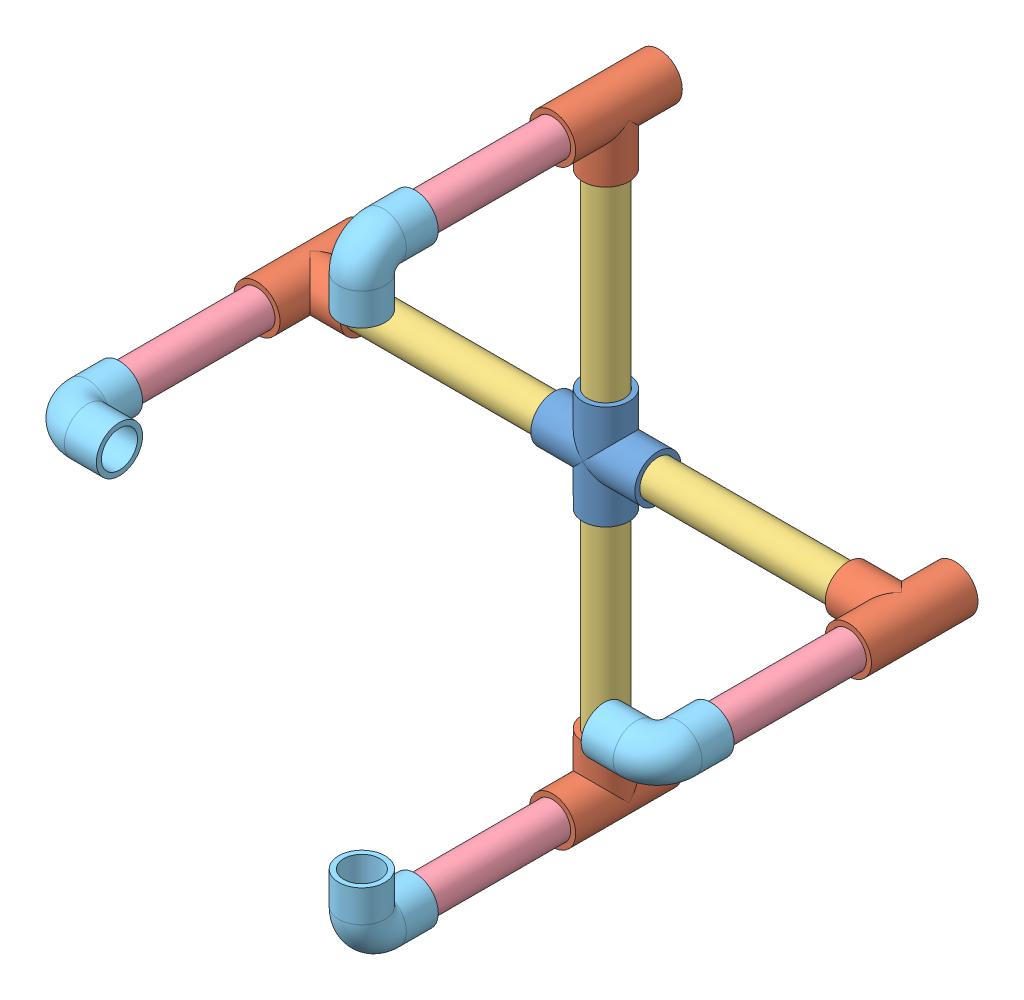
SolidWorks assembly WAYPOINT, configuration Default. Lengths in mm.
Overall size (379.95 379.95 190.93).
17 component instances, 5 part files, 37 mates.
Components (placement in the parent):
- 1-2 PVC CROSS-1: 1-2 PVC CROSS [4880K241] at (26.3836 29.7217 47.5538) size (61.91 61.91 27.56)
- 1-2 PVC TEE-1: 1-2 PVC TEE [4880K41] at (26.3836 -146.472 47.5538) x (0 0 1) z (-1 0 0) size (63.5 45.53 27.56)
- 1-2 PVC TEE-2: 1-2 PVC TEE [4880K41] at (202.5773 29.7217 47.5538) x (0 0 -1) z (0 1 0) size (63.5 45.53 27.56)
- 1-2 PVC TEE-3: 1-2 PVC TEE [4880K41] at (-149.8102 29.7217 47.5538) x (0 0 -1) z (0 -1 0) size (63.5 45.53 27.56)
- 1-2 PVC TEE-4: 1-2 PVC TEE [4880K41] at (26.3836 205.9155 47.5538) x (0 0 1) z (1 0 0) size (63.5 45.53 27.56)
- 1-2 PVC PIPE 15CM-1: 1-2 PVC PIPE 15CM [48925K91] at (26.3836 -58.772 47.5538) x (1 0 0) z (0 1 0) size (21.34 21.34 150)
- 1-2 PVC PIPE 15CM-2: 1-2 PVC PIPE 15CM [48925K91] at (-62.1102 29.7217 47.5538) x (0 0.375424 0.926853) z (-1 0 0) size (21.34 21.34 150)
- 1-2 PVC PIPE 15CM-3: 1-2 PVC PIPE 15CM [48925K91] at (26.3836 118.2155 47.5538) x (1 0 0) z (0 -1 0) size (21.34 21.34 150)
- 1-2 PVC PIPE 15CM-4: 1-2 PVC PIPE 15CM [48925K91] at (114.8773 29.7217 47.5538) x (0 0.732545 -0.680718) z (1 0 0) size (21.34 21.34 150)
- 1-2 PVC PIPE 12CM-1: 1-2 PVC PIPE 12CM [48925K91] at (-149.8102 29.7217 120.2538) x (1 0 0) z (0 0 -1) size (21.34 21.34 120)
- 1-2 PVC PIPE 12CM-2: 1-2 PVC PIPE 12CM [48925K91] at (26.3836 205.9155 120.2538) x (-1 0 0) z (0 0 -1) size (21.34 21.34 120)
- 1-2 PVC PIPE 12CM-3: 1-2 PVC PIPE 12CM [48925K91] at (202.5773 29.7217 120.2538) x (1 0 0) z (0 0 -1) size (21.34 21.34 120)
- 1-2 PVC PIPE 12CM-4: 1-2 PVC PIPE 12CM [48925K91] at (26.3836 -146.472 120.2538) x (0.346484 -0.938056 0) z (0 0 -1) size (21.34 21.34 120)
- 1-2 PVC ELBOW-1: 1-2 PVC ELBOW [4880K21] at (-149.8102 29.7217 192.9538) x (-1 0 0) z (0 -1 0) size (45.53 45.53 27.56)
- 1-2 PVC ELBOW-2: 1-2 PVC ELBOW [4880K21] at (26.3836 205.9155 192.9538) x (0 0 1) z (1 0 0) size (45.53 45.53 27.56)
- 1-2 PVC ELBOW-3: 1-2 PVC ELBOW [4880K21] at (202.5773 29.7217 192.9538) x (1 0 0) z (0 1 0) size (45.53 45.53 27.56)
- 1-2 PVC ELBOW-4: 1-2 PVC ELBOW [4880K21] at (26.3836 -146.472 192.9538) x (0 -1 0) z (1 0 0) size (45.53 45.53 27.56)
Mates (geometry in assembly coordinates):
- Concentric1: concentric aligned: cone of 1-2 PVC CROSS-1 through (57.3398 29.7217 47.5538) axis (-1 0 0); cylinder of 1-2 PVC PIPE 15CM-4 through (189.8773 29.7217 47.5538) axis (-1 0 0) radius 10.668
- Coincident1: coincident anti-aligned: plane of 1-2 PVC CROSS-1 through (39.8773 29.7217 47.5538) normal (1 0 0); plane of 1-2 PVC PIPE 15CM-4 through (39.8773 29.7217 47.5538) normal (-1 0 0)
- Concentric2: concentric anti-aligned: cylinder of 1-2 PVC CROSS-1 through (39.8773 29.7217 47.5538) axis (-1 0 0) radius 13.7795; cylinder of 1-2 PVC PIPE 15CM-2 through (-137.1102 29.7217 47.5538) axis (1 0 0) radius 10.668
- Coincident2: coincident anti-aligned: plane of 1-2 PVC CROSS-1 through (12.8898 29.7217 47.5538) normal (-1 0 0); plane of 1-2 PVC PIPE 15CM-2 through (12.8898 29.7217 47.5538) normal (1 0 0)
- Coincident3: coincident anti-aligned: plane of 1-2 PVC CROSS-1 through (26.3836 43.2155 47.5538) normal (0 1 0); plane of 1-2 PVC PIPE 15CM-3 through (26.3836 43.2155 47.5538) normal (0 -1 0)
- Concentric3: concentric anti-aligned: cone of 1-2 PVC CROSS-1 through (26.3836 60.678 47.5538) axis (0 -1 0); cylinder of 1-2 PVC PIPE 15CM-3 through (26.3836 43.2155 47.5538) axis (0 1 0) radius 10.668
- Coincident4: coincident anti-aligned: plane of 1-2 PVC CROSS-1 through (26.3836 16.228 47.5538) normal (0 -1 0); plane of 1-2 PVC PIPE 15CM-1 through (26.3836 16.228 47.5538) normal (0 1 0)
- Concentric4: concentric anti-aligned: cone of 1-2 PVC CROSS-1 through (26.3836 16.228 47.5538) axis (0 1 0); cylinder of 1-2 PVC PIPE 15CM-1 through (26.3836 16.228 47.5538) axis (0 -1 0) radius 10.668
- Coincident5: coincident anti-aligned: plane of 1-2 PVC TEE-2 through (189.8773 29.7217 47.5538) normal (-1 0 0); plane of 1-2 PVC PIPE 15CM-4 through (189.8773 29.7217 47.5538) normal (1 0 0)
- Concentric5: concentric anti-aligned: cylinder of 1-2 PVC TEE-2 through (202.5773 29.7217 47.5538) axis (1 0 0) radius 13.7795; cylinder of 1-2 PVC PIPE 15CM-4 through (189.8773 29.7217 47.5538) axis (-1 0 0) radius 10.668
- Concentric6: concentric aligned: cylinder of 1-2 PVC PIPE 12CM-3 through (202.5773 29.2349 60.2445) axis (0 -0.038332 0.999265) radius 10.668; cone of 1-2 PVC ELBOW-3 through (202.5773 25.3653 161.1203) axis (0 -0.038332 0.999265)
- Coincident6: coincident anti-aligned: plane of 1-2 PVC PIPE 12CM-3; plane of 1-2 PVC ELBOW-3
- Concentric7: concentric aligned: cone of 1-2 PVC TEE-2 through (202.5773 30.9387 15.8272) axis (0 -0.038332 0.999265); cylinder of 1-2 PVC PIPE 12CM-3 through (202.5773 29.2349 60.2445) axis (0 -0.038332 0.999265) radius 10.668
- Concentric8: concentric aligned: cone of 1-2 PVC TEE-1 through (26.3836 -114.722 47.5538) axis (0 -1 0); cylinder of 1-2 PVC PIPE 15CM-1 through (26.3836 16.228 47.5538) axis (0 -1 0) radius 10.668
- Coincident7: coincident anti-aligned: plane of 1-2 PVC TEE-1 through (26.3836 -133.772 47.5538) normal (0 1 0); plane of 1-2 PVC PIPE 15CM-1 through (26.3836 -133.772 47.5538) normal (0 -1 0)
- Coincident8: coincident anti-aligned: plane of 1-2 PVC TEE-4 through (26.3836 193.2155 47.5538) normal (0 -1 0); plane of 1-2 PVC PIPE 15CM-3 through (26.3836 193.2155 47.5538) normal (0 1 0)
- Concentric9: concentric aligned: cylinder of 1-2 PVC TEE-4 through (26.3836 205.9155 47.5538) axis (0 1 0) radius 13.7795; cylinder of 1-2 PVC PIPE 15CM-3 through (26.3836 43.2155 47.5538) axis (0 1 0) radius 10.668
- Coincident9: coincident anti-aligned: plane of 1-2 PVC TEE-4 through (26.3836 205.9155 60.2538) normal (0 0 1); plane of 1-2 PVC PIPE 12CM-2 through (26.3836 205.9155 60.2538) normal (0 0 -1)
- Concentric10: concentric anti-aligned: cone of 1-2 PVC TEE-4 through (26.3836 205.9155 79.3038) axis (0 0 -1); cylinder of 1-2 PVC PIPE 12CM-2 through (26.3836 205.9155 60.2538) axis (0 0 1) radius 10.668
- Coincident10: coincident anti-aligned: plane of 1-2 PVC PIPE 12CM-2 through (26.3836 205.9155 180.2538) normal (0 0 1); plane of 1-2 PVC ELBOW-2 through (26.3836 205.9155 180.2538) normal (0 0 -1)
- Concentric11: concentric aligned: cylinder of 1-2 PVC PIPE 12CM-2 through (26.3836 205.9155 60.2538) axis (0 0 1) radius 10.668; cone of 1-2 PVC ELBOW-2 through (26.3836 205.9155 180.2538) axis (0 0 1)
- Coincident11: coincident anti-aligned: plane of 1-2 PVC TEE-1 through (26.3836 -146.472 60.2538) normal (0 0 1); plane of 1-2 PVC PIPE 12CM-4 through (26.3836 -146.472 60.2538) normal (0 0 -1)
- Concentric12: concentric anti-aligned: cone of 1-2 PVC TEE-1 through (26.3836 -146.472 79.3038) axis (0 0 -1); cylinder of 1-2 PVC PIPE 12CM-4 through (26.3836 -146.472 60.2538) axis (0 0 1) radius 10.668
- Coincident12: coincident anti-aligned: plane of 1-2 PVC PIPE 12CM-4 through (26.3836 -146.472 180.2538) normal (0 0 1); plane of 1-2 PVC ELBOW-4 through (26.3836 -146.472 180.2538) normal (0 0 -1)
- Concentric13: concentric aligned: cylinder of 1-2 PVC PIPE 12CM-4 through (26.3836 -146.472 60.2538) axis (0 0 1) radius 10.668; cylinder of 1-2 PVC ELBOW-4 through (26.3836 -146.472 192.9538) axis (0 0 1) radius 13.7795
- Coincident13: coincident anti-aligned: plane of 1-2 PVC TEE-3 through (-137.1102 29.7217 47.5538) normal (1 0 0); plane of 1-2 PVC PIPE 15CM-2 through (-137.1102 29.7217 47.5538) normal (-1 0 0)
- Concentric14: concentric anti-aligned: cylinder of 1-2 PVC TEE-3 through (-149.8102 29.7217 47.5538) axis (-1 0 0) radius 13.7795; cylinder of 1-2 PVC PIPE 15CM-2 through (-137.1102 29.7217 47.5538) axis (1 0 0) radius 10.668
- Coincident14: coincident anti-aligned: plane of 1-2 PVC TEE-3 through (-149.8102 29.7217 60.2538) normal (0 0 1); plane of 1-2 PVC PIPE 12CM-1 through (-149.8102 29.7217 60.2538) normal (0 0 -1)
- Concentric15: concentric anti-aligned: cone of 1-2 PVC TEE-3 through (-149.8102 29.7217 60.2538) axis (0 0 -1); cylinder of 1-2 PVC PIPE 12CM-1 through (-149.8102 29.7217 60.2538) axis (0 0 1) radius 10.668
- Coincident15: coincident anti-aligned: plane of 1-2 PVC PIPE 12CM-1 through (-149.8102 29.7217 180.2538) normal (0 0 1); plane of 1-2 PVC ELBOW-1 through (-149.8102 29.7217 180.2538) normal (0 0 -1)
- Concentric16: concentric aligned: cylinder of 1-2 PVC PIPE 12CM-1 through (-149.8102 29.7217 60.2538) axis (0 0 1) radius 10.668; cylinder of 1-2 PVC ELBOW-1 through (-149.8102 29.7217 192.9538) axis (0 0 1) radius 13.7795
- Parallel1: parallel anti-aligned: cone of 1-2 PVC ELBOW-1 through (-137.1102 29.7217 192.9538) axis (-1 0 0); cone of 1-2 PVC ELBOW-3 through (189.8773 29.7217 192.9538) axis (1 0 0)
- Parallel2: parallel anti-aligned: cone of 1-2 PVC ELBOW-2 through (26.3836 174.1655 192.9538) axis (0 1 0); cone of 1-2 PVC ELBOW-4 through (26.3836 -133.772 192.9538) axis (0 -1 0)
- Coincident18: coincident anti-aligned: plane of 1-2 PVC TEE-2 through (202.5773 29.7217 60.2538) normal (0 0 1); plane of 1-2 PVC PIPE 12CM-3 through (202.5773 29.7217 60.2538) normal (0 0 -1)
- Coincident19: coincident aligned: plane of 1-2 PVC TEE-4 through (26.3836 219.695 15.8038) normal (0 0 -1); plane of 1-2 PVC TEE-3 through (-163.5897 29.7217 15.8038) normal (0 0 -1)
- Coincident20: coincident aligned: plane of 1-2 PVC TEE-4 through (26.3836 219.695 15.8038) normal (0 0 -1); plane of 1-2 PVC TEE-1 through (26.3836 -160.2515 15.8038) normal (0 0 -1)
- Coincident21: coincident aligned: plane of 1-2 PVC TEE-4 through (26.3836 219.695 15.8038) normal (0 0 -1); plane of 1-2 PVC TEE-2 through (216.3568 29.7217 15.8038) normal (0 0 -1)
